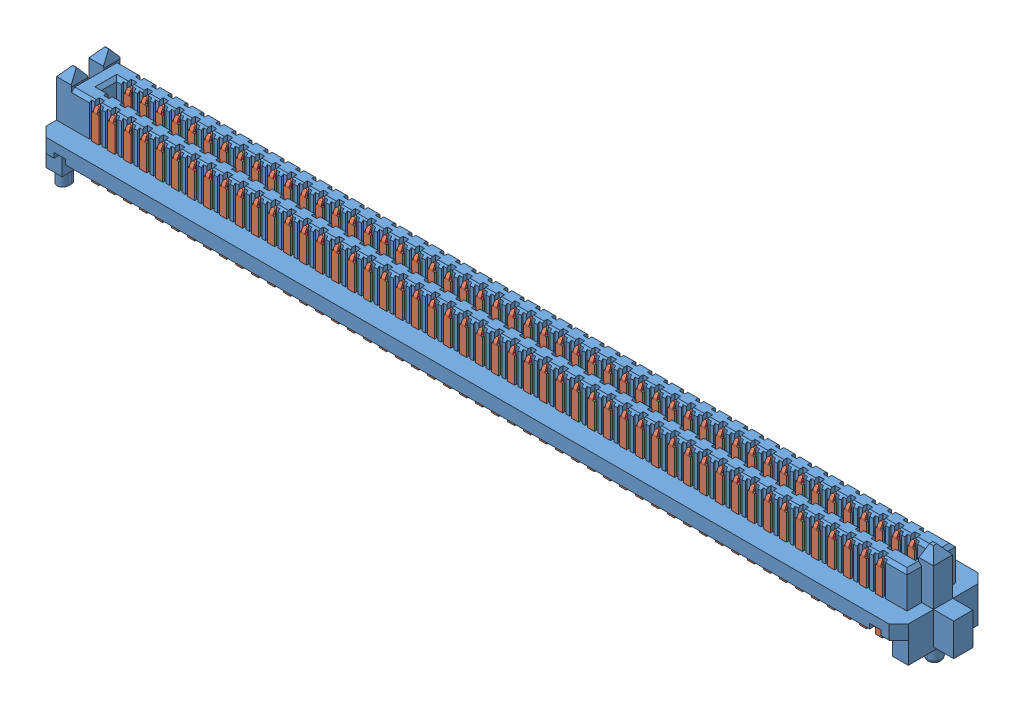
SolidWorks assembly Assem2, configuration Default. Lengths in mm.
Overall size (70.08 7.87 7.06).
5 component instances, 4 part files, 3 mates.
Components (placement in the parent):
- SEAM_50_03_0_L_04_2_A_K_TR-1: SEAM_50_03_0_L_04_2_A_K_TR [Default] at (0 2.8448 0) size (70.08 7.87 7.06)
  - _SEAM_50_03_0_L_04_1_A_K_TR_body_2-1: _SEAM_50_03_0_L_04_1_A_K_TR_body_2 [Default] at origin size (70.08 7.87 7.06)
  - _SEAM_50_03_0_L_04_1_A_K_TR_conn_4-1: _SEAM_50_03_0_L_04_1_A_K_TR_conn_4 [Default] at origin size (67.97 5.25 6.55)
  - _SEAM_K_Pad_04_6-1: _SEAM_K_Pad_04_6 [Default] at (0 2.7432 0) size (5.99 0.13 5.99) (hidden)
  - _SEAM_Triangle_8-1: _SEAM_Triangle_8 [Default] at (32.2834 1.3462 -1.6764) x (-1 0 0) z (0 0 -1) size (1.02 1.27 0.13)
Mates (geometry in assembly coordinates):
- Coincident2: coincident: plane of ? through (32.9692 0 2.7686) normal (0 -1 0)
- Coincident3: coincident: plane of ? through (0 2.8448 0) normal (1 0 0)
- Coincident4: coincident: plane of ? through (0 2.8448 0) normal (0 0 1)
